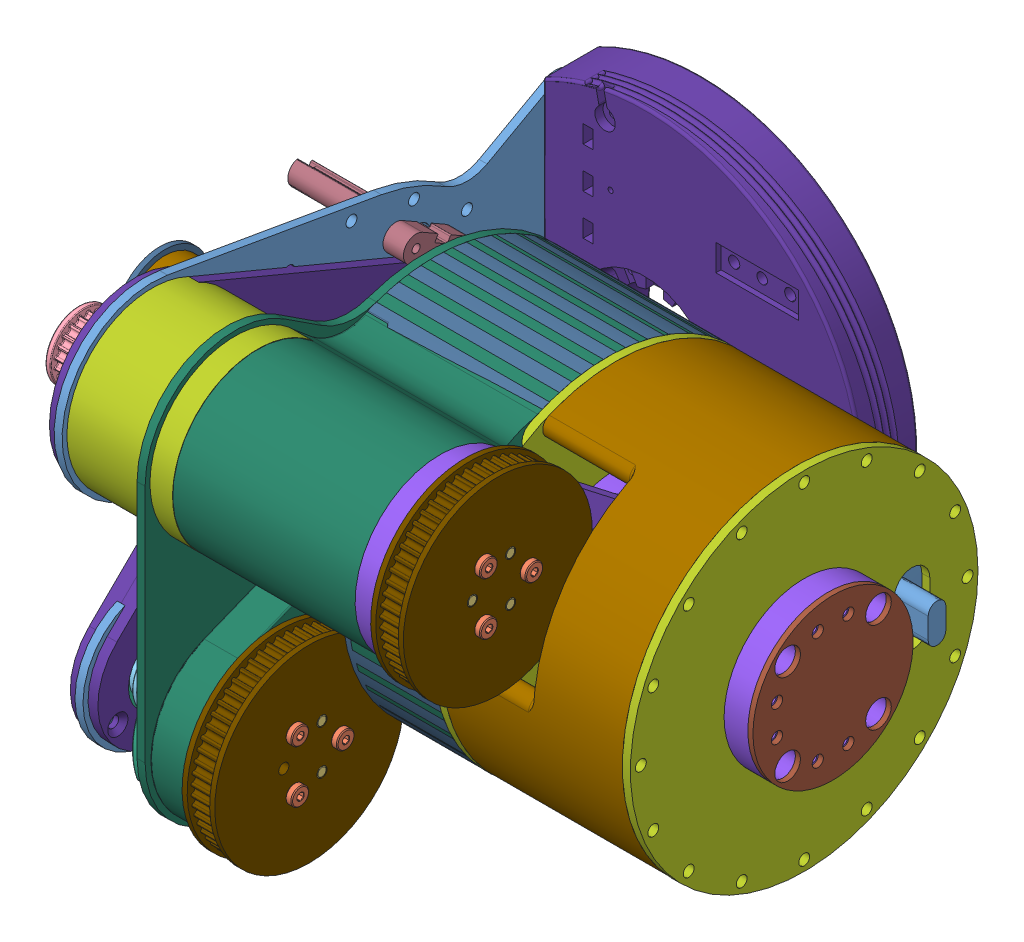
SolidWorks assembly Shoulder Housing, configuration Default. Lengths in mm.
Overall size (215.53 161.21 536.98).
89 component instances, 38 part files, 75 mates.
Components (placement in the parent):
- 0 Dimensions-1: 0 Dimensions [Default] at origin size (179.79 135 536.98)
- SH Motor Assem-1: SH Motor Assem [Default] at (8.4837 0 0) x (0 1 0) z (0 0 1) size (129.63 57.83 129.63)
  - Motor Assem-1: Motor Assem [Default] at origin size (129.63 44.53 129.63)
    - 9225 160kv-1: 9225 160kv [Default] at (0 -18.055 0) x (0.707107 0 0.707107) z (-0.707107 0 0.707107) size (91.66 44.53 91.66)
    - Encoder Magnet-1: Encoder Magnet [Default] at (0 -19.6425 0) size (6.35 3.17 6.35)
    - Magnut hex puck-1: Magnut hex puck [Default] at (0 -18.055 0) x (0.707107 0 0.707107) z (-0.707107 0 0.707107) size (22.91 4.76 22.91)
    - encoder final board-1: encoder final board [Default] at (0 -23.0237 0) x (0 0 -1) z (1 0 0) size (25 2.95 25)
  - Motor Belt Pulley-1: Motor Belt Pulley [Default] at (0 21.7525 0) x (-0.707107 0 -0.707107) z (0.707107 0 -0.707107) size (39.69 19.3 39.69)
  - Bearing 15_24_5mm-1: Bearing 15_24_5mm [Default] at (0 30.9275 0) size (24 5 24)
  - Motor Baseplate^SH Motor Assem-1: Motor Baseplate^SH Motor Assem [Default] at origin size (108.25 2.5 108.25) (virtual)
  - Encoder Mount^SH Motor Assem-1: Encoder Mount^SH Motor Assem [Default] at origin size (49.9 7.4 49.9) (virtual)
- SH Motor Assem-2: SH Motor Assem [Default] at (67.2212 0 0) x (0 1 0) z (0 0 1) size (129.63 57.83 129.63)
  - Motor Assem-1: Motor Assem [Default] at origin size (129.63 44.53 129.63)
    - 9225 160kv-1: 9225 160kv [Default] at (0 -18.055 0) x (0.707107 0 0.707107) z (-0.707107 0 0.707107) size (91.66 44.53 91.66)
    - Encoder Magnet-1: Encoder Magnet [Default] at (0 -19.6425 0) size (6.35 3.17 6.35)
    - Magnut hex puck-1: Magnut hex puck [Default] at (0 -18.055 0) x (0.707107 0 0.707107) z (-0.707107 0 0.707107) size (22.91 4.76 22.91)
    - encoder final board-1: encoder final board [Default] at (0 -23.0237 0) x (0 0 -1) z (1 0 0) size (25 2.95 25)
  - Motor Belt Pulley-1: Motor Belt Pulley [Default] at (0 21.7525 0) x (-0.707107 0 -0.707107) z (0.707107 0 -0.707107) size (39.69 19.3 39.69)
  - Bearing 15_24_5mm-1: Bearing 15_24_5mm [Default] at (0 30.9275 0) size (24 5 24)
  - Motor Baseplate^SH Motor Assem-1: Motor Baseplate^SH Motor Assem [Default] at origin size (108.25 2.5 108.25) (virtual)
  - Encoder Mount^SH Motor Assem-1: Encoder Mount^SH Motor Assem [Default] at origin size (49.9 7.4 49.9) (virtual)
- Shaft^Shoulder Housing-1: Shaft^Shoulder Housing [Default] at origin size (81.5 50.4 45.67) (virtual)
- Shaft Cap^Shoulder Housing-1: Shaft Cap^Shoulder Housing [Default] at origin size (1.59 28.18 28.18) (virtual)
- 95615A120_ZINC-PLATED GRADE 5 STL NYLON-INSERT LOCKNUT-1: 95615A120_ZINC-PLATED GRADE 5 STL NYLON-INSERT LOCKNUT [95615A120] at (-90.2853 0 0) x (0 1 0) z (0 0 1) size (11.11 8.13 12.83)
- 91259A108_ALLOY STEEL SHOULDER SCREW-1: 91259A108_ALLOY STEEL SHOULDER SCREW [91259A108] at (-25.7375 0 0) x (0 0 -1) z (1 0 0) size (11.11 11.11 74.57)
- 91595A114_METRIC ALLOY STEEL DOWEL PIN-1: 91595A114_METRIC ALLOY STEEL DOWEL PIN [91595A114] at (-35.2938 0 -9.525) x (-1 0 0) z (0 0 -1) size (14 3 3)
- 91595A114_METRIC ALLOY STEEL DOWEL PIN-2: 91595A114_METRIC ALLOY STEEL DOWEL PIN [91595A114] at (-35.2938 8.2489 -4.7625) x (-1 0 0) z (0 0.866025 -0.5) size (14 3 3)
- 91595A114_METRIC ALLOY STEEL DOWEL PIN-3: 91595A114_METRIC ALLOY STEEL DOWEL PIN [91595A114] at (-35.2938 8.2489 4.7625) x (-1 0 0) z (0 0.866025 0.5) size (14 3 3)
- 91595A114_METRIC ALLOY STEEL DOWEL PIN-4: 91595A114_METRIC ALLOY STEEL DOWEL PIN [91595A114] at (-35.2938 0 9.525) x (-1 0 0) z (0 0 1) size (14 3 3)
- 91595A114_METRIC ALLOY STEEL DOWEL PIN-5: 91595A114_METRIC ALLOY STEEL DOWEL PIN [91595A114] at (-35.2938 -8.2489 4.7625) x (-1 0 0) z (0 -0.866025 0.5) size (14 3 3)
- 91595A114_METRIC ALLOY STEEL DOWEL PIN-6: 91595A114_METRIC ALLOY STEEL DOWEL PIN [91595A114] at (-35.2938 -8.2489 -4.7625) x (-1 0 0) z (0 -0.866025 -0.5) size (14 3 3)
- .500 plastight 90380A110_PHILLIPS THREAD-FORMING SCREW FOR PLASTIC-1: .500 plastight 90380A110_PHILLIPS THREAD-FORMING SCREW FOR PLASTIC [90380A110] at (-110.5313 9.525 0) x (0 -1 0) z (-1 0 0) size (5.56 5.56 15.22)
- .500 plastight 90380A110_PHILLIPS THREAD-FORMING SCREW FOR PLASTIC-2: .500 plastight 90380A110_PHILLIPS THREAD-FORMING SCREW FOR PLASTIC [90380A110] at (-110.5313 7.7059 5.5987) x (0 -0.809017 -0.587785) z (-1 0 0) size (5.56 5.56 15.22)
- .500 plastight 90380A110_PHILLIPS THREAD-FORMING SCREW FOR PLASTIC-3: .500 plastight 90380A110_PHILLIPS THREAD-FORMING SCREW FOR PLASTIC [90380A110] at (-110.5313 2.9434 9.0588) x (0 -0.309017 -0.951057) z (-1 0 0) size (5.56 5.56 15.22)
- .500 plastight 90380A110_PHILLIPS THREAD-FORMING SCREW FOR PLASTIC-4: .500 plastight 90380A110_PHILLIPS THREAD-FORMING SCREW FOR PLASTIC [90380A110] at (-110.5313 -2.9434 9.0588) x (0 0.309017 -0.951057) z (-1 0 0) size (5.56 5.56 15.22)
- .500 plastight 90380A110_PHILLIPS THREAD-FORMING SCREW FOR PLASTIC-5: .500 plastight 90380A110_PHILLIPS THREAD-FORMING SCREW FOR PLASTIC [90380A110] at (-110.5313 -7.7059 5.5987) x (0 0.809017 -0.587785) z (-1 0 0) size (5.56 5.56 15.22)
- .500 plastight 90380A110_PHILLIPS THREAD-FORMING SCREW FOR PLASTIC-6: .500 plastight 90380A110_PHILLIPS THREAD-FORMING SCREW FOR PLASTIC [90380A110] at (-110.5313 -9.525 0) x (0 1 0) z (-1 0 0) size (5.56 5.56 15.22)
- .500 plastight 90380A110_PHILLIPS THREAD-FORMING SCREW FOR PLASTIC-7: .500 plastight 90380A110_PHILLIPS THREAD-FORMING SCREW FOR PLASTIC [90380A110] at (-110.5313 -7.7059 -5.5987) x (0 0.809017 0.587785) z (-1 0 0) size (5.56 5.56 15.22)
- .500 plastight 90380A110_PHILLIPS THREAD-FORMING SCREW FOR PLASTIC-8: .500 plastight 90380A110_PHILLIPS THREAD-FORMING SCREW FOR PLASTIC [90380A110] at (-110.5313 -2.9434 -9.0588) x (0 0.309017 0.951057) z (-1 0 0) size (5.56 5.56 15.22)
- .500 plastight 90380A110_PHILLIPS THREAD-FORMING SCREW FOR PLASTIC-9: .500 plastight 90380A110_PHILLIPS THREAD-FORMING SCREW FOR PLASTIC [90380A110] at (-110.5313 2.9434 -9.0588) x (0 -0.309017 0.951057) z (-1 0 0) size (5.56 5.56 15.22)
- .500 plastight 90380A110_PHILLIPS THREAD-FORMING SCREW FOR PLASTIC-10: .500 plastight 90380A110_PHILLIPS THREAD-FORMING SCREW FOR PLASTIC [90380A110] at (-110.5313 7.7059 -5.5987) x (0 -0.809017 0.587785) z (-1 0 0) size (5.56 5.56 15.22)
- SH Axle Plate^Shoulder Housing-1: SH Axle Plate^Shoulder Housing [Default] at origin size (2.5 130.7 144.27) (virtual)
- .500 plastight 90380A110_PHILLIPS THREAD-FORMING SCREW FOR PLASTIC-11: .500 plastight 90380A110_PHILLIPS THREAD-FORMING SCREW FOR PLASTIC [90380A110] at (-54.7688 -9.525 0) x (0 1 0) z (1 0 0) size (5.56 5.56 15.22)
- .500 plastight 90380A110_PHILLIPS THREAD-FORMING SCREW FOR PLASTIC-12: .500 plastight 90380A110_PHILLIPS THREAD-FORMING SCREW FOR PLASTIC [90380A110] at (-54.7688 9.525 0) x (0 -1 0) z (1 0 0) size (5.56 5.56 15.22)
- Bearing 25_37_7mm-1: Bearing 25_37_7mm [Default] at (-32.675 -37.3248 62.1189) size (7 37 37)
- Bearing 25_37_7mm-2: Bearing 25_37_7mm [Default] at (-22.65 -37.3248 62.1189) size (7 37 37)
- Bearing 25_37_7mm-3: Bearing 25_37_7mm [Default] at (36.0875 37.3248 62.1189) size (7 37 37)
- Bearing 25_37_7mm-4: Bearing 25_37_7mm [Default] at (-32.675 37.3248 62.1189) size (7 37 37)
- big roller-1: big roller [Default] at (-25.4 0 -68.4438) x (0.965911 0.258873 0) z (0.258873 -0.965911 0) size (114.33 17.73 136.26)
- Outrigged Large Pulley Assem-1: Outrigged Large Pulley Assem [Default] at (45.4687 37.3248 62.1189) x (0 0 -1) z (0 -1 0) size (58.88 27.2 58.88)
  - Outrigged Pulley Big-1: Outrigged Pulley Big [Default] at origin size (58.88 10.97 58.88)
  - m3 Square Nut-1: m3 Square Nut [Default] at (9.4437 -18.6625 0) size (5.5 2.5 5.5)
  - 92855A317_TYPE 18-8 SS LOW PROFILE SOCKET CAP SCREW-1: 92855A317_TYPE 18-8 SS LOW PROFILE SOCKET CAP SCREW [92855A317] at (9.4437 -19.9125 0) x (1 0 0) z (0 -1 0) size (5.5 5.5 27.2)
  - Dowel 98381A471_ALLOY STEEL DOWEL PIN-1: Dowel 98381A471_ALLOY STEEL DOWEL PIN [98381A471] at (-7.9375 -1.2625 0) x (0 -1 0) z (-1 0 0) size (12.7 3.17 3.17) (hidden)
  - Dowel 98381A471_ALLOY STEEL DOWEL PIN-2: Dowel 98381A471_ALLOY STEEL DOWEL PIN [98381A471] at (3.9688 -1.2625 -6.8741) x (0 -1 0) z (0.5 0 -0.866025) size (12.7 3.17 3.17)
  - Dowel 98381A471_ALLOY STEEL DOWEL PIN-3: Dowel 98381A471_ALLOY STEEL DOWEL PIN [98381A471] at (3.9688 -1.2625 6.8741) x (0 -1 0) z (0.5 0 0.866025) size (12.7 3.17 3.17)
  - 92855A317_TYPE 18-8 SS LOW PROFILE SOCKET CAP SCREW-2: 92855A317_TYPE 18-8 SS LOW PROFILE SOCKET CAP SCREW [92855A317] at (-4.7219 -19.9125 8.1785) x (-0.5 0 0.866025) z (0 -1 0) size (5.5 5.5 27.2)
  - 92855A317_TYPE 18-8 SS LOW PROFILE SOCKET CAP SCREW-3: 92855A317_TYPE 18-8 SS LOW PROFILE SOCKET CAP SCREW [92855A317] at (-4.7219 -19.9125 -8.1785) x (-0.5 0 -0.866025) z (0 -1 0) size (5.5 5.5 27.2)
  - m3 Square Nut-2: m3 Square Nut [Default] at (-4.7219 -18.6625 8.1785) x (-0.5 0 0.866025) z (-0.866025 0 -0.5) size (5.5 2.5 5.5)
  - m3 Square Nut-3: m3 Square Nut [Default] at (-4.7219 -18.6625 -8.1785) x (-0.5 0 -0.866025) z (0.866025 0 -0.5) size (5.5 2.5 5.5)
- Outrigged Pulley Small Long-1: Outrigged Pulley Small Long [Default] at (-71.8938 37.3248 62.1189) x (0 -1 0) z (0 0 -1) size (26.59 125.12 26.59)
- Outrigged Large Pulley Assem-2: Outrigged Large Pulley Assem [Default] at (-13.2688 -37.3248 62.1189) x (0 0 -1) z (0 -1 0) size (58.88 27.2 58.88)
  - Outrigged Pulley Big-1: Outrigged Pulley Big [Default] at origin size (58.88 10.97 58.88)
  - m3 Square Nut-1: m3 Square Nut [Default] at (9.4437 -18.6625 0) size (5.5 2.5 5.5)
  - 92855A317_TYPE 18-8 SS LOW PROFILE SOCKET CAP SCREW-1: 92855A317_TYPE 18-8 SS LOW PROFILE SOCKET CAP SCREW [92855A317] at (9.4437 -19.9125 0) x (1 0 0) z (0 -1 0) size (5.5 5.5 27.2)
  - Dowel 98381A471_ALLOY STEEL DOWEL PIN-1: Dowel 98381A471_ALLOY STEEL DOWEL PIN [98381A471] at (-7.9375 -1.2625 0) x (0 -1 0) z (-1 0 0) size (12.7 3.17 3.17) (hidden)
  - Dowel 98381A471_ALLOY STEEL DOWEL PIN-2: Dowel 98381A471_ALLOY STEEL DOWEL PIN [98381A471] at (3.9688 -1.2625 -6.8741) x (0 -1 0) z (0.5 0 -0.866025) size (12.7 3.17 3.17)
  - Dowel 98381A471_ALLOY STEEL DOWEL PIN-3: Dowel 98381A471_ALLOY STEEL DOWEL PIN [98381A471] at (3.9688 -1.2625 6.8741) x (0 -1 0) z (0.5 0 0.866025) size (12.7 3.17 3.17)
  - 92855A317_TYPE 18-8 SS LOW PROFILE SOCKET CAP SCREW-2: 92855A317_TYPE 18-8 SS LOW PROFILE SOCKET CAP SCREW [92855A317] at (-4.7219 -19.9125 8.1785) x (-0.5 0 0.866025) z (0 -1 0) size (5.5 5.5 27.2)
  - 92855A317_TYPE 18-8 SS LOW PROFILE SOCKET CAP SCREW-3: 92855A317_TYPE 18-8 SS LOW PROFILE SOCKET CAP SCREW [92855A317] at (-4.7219 -19.9125 -8.1785) x (-0.5 0 -0.866025) z (0 -1 0) size (5.5 5.5 27.2)
  - m3 Square Nut-2: m3 Square Nut [Default] at (-4.7219 -18.6625 8.1785) x (-0.5 0 0.866025) z (-0.866025 0 -0.5) size (5.5 2.5 5.5)
  - m3 Square Nut-3: m3 Square Nut [Default] at (-4.7219 -18.6625 -8.1785) x (-0.5 0 -0.866025) z (0.866025 0 -0.5) size (5.5 2.5 5.5)
- Outrigged Pulley Small Short-2: Outrigged Pulley Small Short [Default] at (-44.9063 -37.3248 62.1189) x (0 -1 0) z (0 0 -1) size (27 47.31 27)
- Bearing Holder^Shoulder Housing-1: Bearing Holder^Shoulder Housing [Default] at origin size (3.17 53 53) (virtual)
- Bearing Nut^Shoulder Housing-1: Bearing Nut^Shoulder Housing [Default] at origin size (32.88 53 53) (hidden, virtual)
- Center Distance Locker Outrigged^Shoulder Housing-1: Center Distance Locker Outrigged^Shoulder Housing [Default] at origin size (6.21 88.78 113.57) (virtual)
- Motor Shroud Upper^Shoulder Housing-1: Motor Shroud Upper^Shoulder Housing [Default] at origin size (56.24 108.25 108.25) (virtual)
- Motor Shroud Lower^Shoulder Housing-1: Motor Shroud Lower^Shoulder Housing [Default] at (22.6087 0 0) x (0 1 0) z (-1 0 0) size (108.25 108.25 54.19) (hidden, virtual)
- Encoder Clamp ^Shoulder Housing-1: Encoder Clamp ^Shoulder Housing [Default] at origin size (1.59 49.9 49.9) (virtual)
- Hall Sensor Mount-1: Hall Sensor Mount [Default] at (-31.2938 0 -23.0188) x (0 -1 0) z (0 0 -1) size (23.81 8.73 7.94)
- Hall Sensor Mount Tall-1: Hall Sensor Mount Tall [Default] at (-57.15 35.7452 -20.6375) x (0 -0.5 -0.866025) z (0 0.866025 -0.5) size (23.81 42.86 7.94)
- Long Pulley Sleeve^Shoulder Housing-1: Long Pulley Sleeve^Shoulder Housing [Default] at (-29.175 37.3248 62.1189) x (0 0 -1) z (1 0 0) size (28.57 28.57 61.36) (virtual)
- Axle Plate Motor Bearing Support Double^Shoulder Housing-1: Axle Plate Motor Bearing Support Double^Shoulder Housing [Default] at origin size (64.17 127.52 142.68)
- Bearing 15_24_5mm-2: Bearing 15_24_5mm [Default] at (-58.4 -37.3248 62.1189) x (0 -1 0) z (0 0 1) size (24 5 24)
- Bearing 25_37_7mm-6: Bearing 25_37_7mm [Default] at (-58.4 37.3248 62.1189) size (7 37 37)
- Bearing 45_58_7mm-2: Bearing 45_58_7mm [Default] at (-58.4 0 0) x (0 0 -1) z (1 0 0) size (58 58 7)
- Copy of Copy of CenterDistanceLocker^Shoulder Housing-1: Copy of Copy of CenterDistanceLocker^Shoulder Housing [Default] at origin size (62.69 121.02 125.49) (hidden, virtual)
- Short Outrigged Pulley Cap^Shoulder Housing-1: Short Outrigged Pulley Cap^Shoulder Housing [Default] at origin size (1.59 17 17) (virtual)
- Part2^Shoulder Housing-1: Part2^Shoulder Housing [Default] at origin size (2.5 124.2 162.69) (virtual)
Mates (geometry in assembly coordinates):
- Coincident1: coincident aligned: line of 0 Dimensions-1 through (0 50.8 -122.6938) axis (0 0 1); line of SH Motor Assem-1 through (0 63.6157 -27.8354) axis (0 0 1)
- Coincident2: coincident aligned: line of 0 Dimensions-1 through (0 50.8 -122.6938) axis (0 0 1); line of SH Motor Assem-2 through (0 63.6157 30.9021) axis (0 0 1)
- Coincident3: coincident aligned: plane of SH Motor Assem-1 through (8.4837 0 0) normal (0 0 1)
- Coincident4: coincident aligned: plane of SH Motor Assem-2 through (67.2212 0 0) normal (0 0 1)
- Coincident5: coincident anti-aligned: plane of Shaft^Shoulder Housing-1 through (-136.4062 0 0) normal (-1 0 0); plane of 95615A120_ZINC-PLATED GRADE 5 STL NYLON-INSERT LOCKNUT-1 through (-136.4062 0 -6.4158) normal (1 0 0)
- Coincident6: coincident: line of 0 Dimensions-1 through (0 50.8 -122.6938) axis (0 0 1); point of 95615A120_ZINC-PLATED GRADE 5 STL NYLON-INSERT LOCKNUT-1
- Coincident7: coincident aligned: plane of 95615A120_ZINC-PLATED GRADE 5 STL NYLON-INSERT LOCKNUT-1 through (-90.2853 0 0) normal (0 1 0)
- Coincident8: coincident anti-aligned: plane of Shaft^Shoulder Housing-1 through (-90.2853 0 0) normal (-1 0 0); plane of 95615A120_ZINC-PLATED GRADE 5 STL NYLON-INSERT LOCKNUT-1 through (-90.2853 0 -6.4158) normal (1 0 0)
- Concentric1: concentric anti-aligned: line of 0 Dimensions-1 through (0 50.8 -122.6938) axis (0 0 1); cylinder of 91259A108_ALLOY STEEL SHOULDER SCREW-1 through (-99.5563 0 0) axis (-1 0 0) radius 3.9688
- Coincident9: coincident anti-aligned: plane of 91259A108_ALLOY STEEL SHOULDER SCREW-1 through (-31.2938 -5.5563 0) normal (-1 0 0); plane of Shaft^Shoulder Housing-1 through (-31.2938 0 0) normal (1 0 0)
- Coincident10: coincident aligned: plane of 91259A108_ALLOY STEEL SHOULDER SCREW-1 through (-25.7375 0 0) normal (0 1 0)
- Tangent1: tangent anti-aligned: plane of Shaft^Shoulder Housing-1 through (-42.2938 0 -9.525) normal (1 0 0); sphere of 91595A114_METRIC ALLOY STEEL DOWEL PIN-1
- Concentric2: concentric anti-aligned: cylinder of Shaft^Shoulder Housing-1 through (-42.2938 0 -9.525) axis (1 0 0) radius 1.5; cylinder of 91595A114_METRIC ALLOY STEEL DOWEL PIN-1 through (-28.2938 0 -9.525) axis (-1 0 0) radius 1.5
- Coincident11: coincident aligned: plane of 91595A114_METRIC ALLOY STEEL DOWEL PIN-1 through (-35.2938 0 -9.525) normal (0 1 0)
- Concentric3: concentric anti-aligned: cylinder of Shaft^Shoulder Housing-1 through (-102.5938 9.525 0) axis (-1 0 0) radius 1.27; line of .500 plastight 90380A110_PHILLIPS THREAD-FORMING SCREW FOR PLASTIC-1 through (18.2987 -120.0353 9.525) axis (0 1 0)
- Coincident12: coincident aligned: plane of .500 plastight 90380A110_PHILLIPS THREAD-FORMING SCREW FOR PLASTIC-1 through (-110.5313 9.525 0) normal (0 0 1)
- Coincident13: coincident anti-aligned: plane of Shaft Cap^Shoulder Housing-1 through (-116.8813 0 0) normal (-1 0 0); plane of .500 plastight 90380A110_PHILLIPS THREAD-FORMING SCREW FOR PLASTIC-1 through (-116.8813 9.525 0) normal (1 0 0)
- Concentric4: concentric anti-aligned: cylinder of Shaft^Shoulder Housing-1 through (-52.8438 -9.525 0) axis (1 0 0) radius 1.27; line of .500 plastight 90380A110_PHILLIPS THREAD-FORMING SCREW FOR PLASTIC-11 through (18.2987 -45.2647 -9.525) axis (0 -1 0)
- Coincident15: coincident: plane of .500 plastight 90380A110_PHILLIPS THREAD-FORMING SCREW FOR PLASTIC-11 through (-54.7688 -9.525 0) normal (0 0 1)
- Coincident21: coincident anti-aligned: plane of 0 Dimensions-1 through (-44.9063 0 0) normal (1 0 0); plane of Outrigged Pulley Small Short-2 through (-44.9063 -37.3248 62.1189) normal (-1 0 0)
- Coincident23: coincident aligned: line of Outrigged Pulley Small Short-2 through (-52.5232 -37.3248 62.1189) axis (1 0 0)
- Coincident24: coincident aligned: line of Bearing 25_37_7mm-4 through (-36.525 37.3248 62.1189) axis (1 0 0)
- Coincident25: coincident aligned: line of Bearing 25_37_7mm-3 through (32.2375 37.3248 62.1189) axis (1 0 0)
- Coincident26: coincident aligned: line of Bearing 25_37_7mm-2 through (-26.5 -37.3248 62.1189) axis (1 0 0)
- Coincident27: coincident aligned: line of Bearing 25_37_7mm-1 through (-36.525 -37.3248 62.1189) axis (1 0 0)
- Parallel1: parallel aligned: plane of Bearing 25_37_7mm-1 through (-32.675 -37.3248 62.1189) normal (0 1 0)
- Parallel2: parallel aligned: plane of Bearing 25_37_7mm-2 through (-22.65 -37.3248 62.1189) normal (0 1 0)
- Parallel3: parallel aligned: plane of Bearing 25_37_7mm-3 through (36.0875 37.3248 62.1189) normal (0 1 0)
- Parallel4: parallel aligned: plane of Bearing 25_37_7mm-4 through (-32.675 37.3248 62.1189) normal (0 1 0)
- Coincident32: coincident aligned: line of 0 Dimensions-1 through (-25.4 0 0) axis (0 0 -1); line of big roller-1 through (-25.4 0 -13.4438) axis (0 0 -1)
- Coincident33: coincident: line of 0 Dimensions-1 through (-57.15 -59.5667 -59.65) axis (0 1 0); plane of big roller-1 through (-57.15 0 -68.4438) normal (-1 0 0)
- Coincident34: coincident anti-aligned: plane of 0 Dimensions-1 through (0 0 -59.65) normal (0 0 -1); plane of big roller-1 through (-58.8638 57.5246 -59.65) normal (0 0 1)
- Coincident35: coincident aligned: plane of SH Motor Assem-2/Bearing 15_24_5mm-1 through (19.2875 0 0) normal (1 0 0); plane of Bearing 25_37_7mm-3 through (19.2875 27.7331 66.9535) normal (1 0 0)
- Coincident36: coincident aligned: plane of SH Motor Assem-1/Bearing 15_24_5mm-1 through (-39.45 0 0) normal (1 0 0); plane of Bearing 25_37_7mm-2 through (-39.45 -27.7331 66.9535) normal (1 0 0)
- Distance3: distance = 6.35 mm anti-aligned: plane of SH Motor Assem-1/Bearing 15_24_5mm-1 through (-24.9437 0 0) normal (-1 0 0); plane of SH Axle Plate^Shoulder Housing-1 through (-31.2938 -37.3248 62.1189) normal (1 0 0)
- Coincident38: coincident aligned: plane of Bearing 25_37_7mm-1 through (-36.175 -37.3248 62.1189) normal (-1 0 0); plane of Bearing 25_37_7mm-4 through (-36.175 37.3248 62.1189) normal (-1 0 0)
- Distance4: distance = 2.3813 mm aligned: plane of SH Axle Plate^Shoulder Housing-1 through (-33.7938 -37.3248 62.1189) normal (-1 0 0); plane of Bearing 25_37_7mm-1 through (-36.175 -37.3248 62.1189) normal (-1 0 0)
- Coincident39: coincident anti-aligned: line of Outrigged Large Pulley Assem-1 through (54.0314 37.3248 62.1189) axis (-1 0 0)
- Coincident40: coincident anti-aligned: line of Outrigged Large Pulley Assem-2 through (-4.7061 -37.3248 62.1189) axis (-1 0 0)
- Parallel5: parallel anti-aligned: plane of Outrigged Large Pulley Assem-1 through (45.4687 37.3248 62.1189) normal (0 -1 0)
- Parallel6: parallel anti-aligned: plane of Outrigged Large Pulley Assem-2 through (-13.2688 -37.3248 62.1189) normal (0 -1 0)
- Coincident43: coincident anti-aligned: plane of Bearing 25_37_7mm-2 through (-19.15 -37.3248 62.1189) normal (1 0 0); plane of Outrigged Large Pulley Assem-2/Outrigged Pulley Big-1 through (-19.15 -37.3248 74.6189) normal (-1 0 0)
- Coincident44: coincident anti-aligned: plane of Bearing 25_37_7mm-3 through (39.5875 37.3248 62.1189) normal (1 0 0); plane of Outrigged Large Pulley Assem-1/Outrigged Pulley Big-1 through (39.5875 37.3248 74.6189) normal (-1 0 0)
- Parallel8: parallel anti-aligned: plane of Outrigged Pulley Small Short-2 through (-44.9063 -37.3248 62.1189) normal (0 0 -1)
- Coincident47: coincident aligned: plane of 0 Dimensions-1 through (-71.8938 0 0) normal (-1 0 0); plane of Outrigged Pulley Small Long-1 through (-71.8938 37.3248 62.1189) normal (-1 0 0)
- Coincident48: coincident aligned: line of 0 Dimensions-1 through (-61.7078 37.3248 62.1189) axis (1 0 0); line of Outrigged Pulley Small Long-1 through (-77.9736 37.3248 62.1189) axis (1 0 0)
- Parallel9: parallel anti-aligned: plane of Outrigged Pulley Small Long-1 through (-71.8938 37.3248 62.1189) normal (0 -1 0)
- Coincident49: coincident anti-aligned: plane of SH Motor Assem-1 through (-13.2688 0 0) normal (-1 0 0); plane of Outrigged Large Pulley Assem-2 through (-13.2688 -37.3248 62.1189) normal (1 0 0)
- Coincident50: coincident anti-aligned: plane of SH Motor Assem-2 through (45.4687 0 0) normal (-1 0 0); plane of Outrigged Large Pulley Assem-1 through (45.4687 37.3248 62.1189) normal (1 0 0)
- InPlace1: in place: plane of ? through (3.1025 0 0) normal (-1 0 0); plane of ? through (3.1025 0 0) normal (-1 0 0); moOrthogonalPlaneRef_w of ? through (3.1025 0 0) normal (-1 0 0); plane of ? through (3.1025 0 0) normal (0 1 0); plane of ? through (3.1025 0 0) normal (-1 0 0); plane of ? through (3.1025 0 0) normal (0 0 1); plane of ? through (22.6087 0 0) normal (-1 0 0); unknown of Motor Shroud Lower^Shoulder Housing-1
- Coincident51: coincident aligned: plane of SH Motor Assem-1/Motor Baseplate^SH Motor Assem-1; plane of Motor Shroud Lower^Shoulder Housing-1
- Coincident52: coincident aligned: moOrthogonalPlaneRef_w of SH Motor Assem-1/Motor Baseplate^SH Motor Assem-1 through (22.6087 0 0) normal (0 0 -1); plane of Motor Shroud Lower^Shoulder Housing-1 through (22.6087 0 0) normal (0 0 -1)
- Coincident53: coincident anti-aligned: moOrthogonalPlaneRef_w of SH Motor Assem-1/Motor Baseplate^SH Motor Assem-1 through (22.6087 0 0) normal (0 -1 0); plane of Motor Shroud Lower^Shoulder Housing-1 through (22.6087 0 0) normal (0 1 0)
- Coincident54: coincident: line of 0 Dimensions-1 through (-24.9437 0 -25.4) axis (0 0 1); plane of SH Motor Assem-1/Bearing 15_24_5mm-1 through (-24.9437 0 0) normal (-1 0 0)
- Coincident55: coincident: line of 0 Dimensions-1 through (33.7938 0 25.4) axis (0 0 -1); plane of SH Motor Assem-2/Bearing 15_24_5mm-1 through (33.7938 0 0) normal (-1 0 0)
- Concentric5: concentric anti-aligned: cylinder of SH Axle Plate^Shoulder Housing-1 through (-31.2938 0 -23.0188) axis (-1 0 0) radius 3.9688; cylinder of Hall Sensor Mount-1 through (-33.675 0 -23.0188) axis (1 0 0) radius 3.9688
- Parallel10: parallel anti-aligned: plane of Hall Sensor Mount-1 through (-31.2938 0 -23.0188) normal (0 0 -1)
- Coincident57: coincident anti-aligned: plane of SH Axle Plate^Shoulder Housing-1 through (-31.2938 -37.3248 62.1189) normal (1 0 0); plane of Hall Sensor Mount-1 through (-31.2938 7.9375 -23.0188) normal (-1 0 0)
- Coincident58: coincident anti-aligned: plane of Part2^Shoulder Housing-1 through (-57.15 0 0) normal (1 0 0); plane of Hall Sensor Mount Tall-1 through (-57.15 39.7139 -13.7634) normal (-1 0 0)
- InPlace2: in place: plane of ? through (-48.6813 37.3248 62.1189) normal (1 0 0); plane of ? through (-48.6813 0 0) normal (1 0 0); plane of ? through (-48.6813 37.3248 62.1189) normal (1 0 0); plane of ? through (-48.6813 0 0) normal (0 1 0); plane of ? through (-48.6813 37.3248 62.1189) normal (1 0 0); plane of ? through (-48.6813 0 0) normal (0 0 -1); plane of Bearing 25_37_7mm-4 through (-29.175 37.3248 62.1189) normal (1 0 0); unknown of Long Pulley Sleeve^Shoulder Housing-1
- Coincident59: coincident aligned: plane of Bearing 25_37_7mm-4; plane of Long Pulley Sleeve^Shoulder Housing-1
- Coincident60: coincident aligned: moOrthogonalPlaneRef_w of Bearing 25_37_7mm-4 through (-29.175 37.3248 62.1189) normal (0 1 0); plane of Long Pulley Sleeve^Shoulder Housing-1 through (-29.175 37.3248 62.1189) normal (0 1 0)
- Coincident61: coincident anti-aligned: moOrthogonalPlaneRef_w of Bearing 25_37_7mm-4 through (-29.175 37.3248 62.1189) normal (0 0 1); plane of Long Pulley Sleeve^Shoulder Housing-1 through (-29.175 37.3248 62.1189) normal (0 0 -1)
- Coincident59: coordinate: unknown of Axle Plate Motor Bearing Support Double^Shoulder Housing-1
- Concentric15: concentric anti-aligned: line of 0 Dimensions-1 through (-61.0816 -37.3248 62.1189) axis (1 0 0); cylinder of Bearing 15_24_5mm-2 through (-55.9 -37.3248 62.1189) axis (-1 0 0) radius 7.5
- Coincident70: coincident anti-aligned: plane of 0 Dimensions-1 through (-58.4 0 0) normal (-1 0 0); plane of Bearing 15_24_5mm-2 through (-58.4 -37.3248 62.1189) normal (1 0 0)
- Parallel15: parallel aligned: plane of Bearing 15_24_5mm-2 through (-58.4 -37.3248 62.1189) normal (0 0 1)
- Concentric16: concentric anti-aligned: line of 0 Dimensions-1 through (-61.7078 37.3248 62.1189) axis (1 0 0); cylinder of Bearing 25_37_7mm-6 through (-54.9 37.3248 62.1189) axis (-1 0 0) radius 12.5
- Parallel16: parallel aligned: plane of Bearing 25_37_7mm-6 through (-58.4 37.3248 62.1189) normal (0 0 1)
- Coincident71: coincident anti-aligned: plane of 0 Dimensions-1 through (-58.4 0 0) normal (-1 0 0); plane of Bearing 25_37_7mm-6 through (-58.4 37.3248 62.1189) normal (1 0 0)
- Coincident72: coincident anti-aligned: plane of 0 Dimensions-1 through (-58.4 0 0) normal (-1 0 0); plane of Bearing 45_58_7mm-2 through (-58.4 0 0) normal (1 0 0)
- Coincident73: coincident aligned: plane of Bearing 45_58_7mm-2 through (-58.4 0 0) normal (0 1 0)
- Concentric17: concentric: cylinder of Bearing 45_58_7mm-2 through (-54.9 0 0) axis (-1 0 0) radius 22.5
- Concentric18: concentric anti-aligned: cylinder of Hall Sensor Mount Tall-1 through (-93.6625 35.7452 -20.6375) axis (1 0 0) radius 3.9688; cylinder of Part2^Shoulder Housing-1 through (-57.15 35.7452 -20.6375) axis (-1 0 0) radius 3.9688
- Concentric19: concentric aligned: cylinder of Hall Sensor Mount Tall-1 through (-50.8 39.7139 -13.7634) axis (-1 0 0) radius 1.27; cylinder of Part2^Shoulder Housing-1 through (-57.15 39.7139 -13.7634) axis (-1 0 0) radius 1.7145
